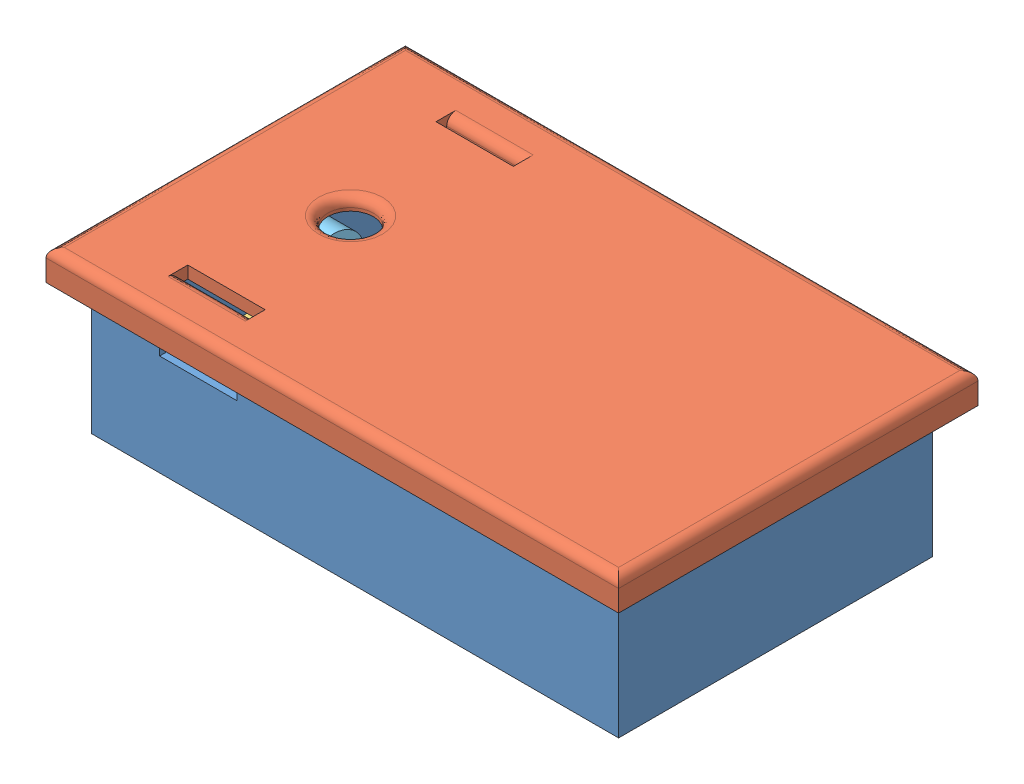
SolidWorks assembly QuadAssembly, configuration Default. Lengths in mm.
Overall size (190.29 53 118).
5 component instances, 5 part files, 12 mates.
Components (placement in the parent):
- ElectronicsHousing_QuadV2-1: ElectronicsHousing_QuadV2 [Default] at (-86.5 4 0) size (173 49 103)
- TopCover_QuadV1-1: TopCover_QuadV1 [Default] at (-86.5 49 0) x (0 0 -1) z (1 0 0) size (118 10 188)
- MockQuadPCB-1: MockQuadPCB [Default] at (-123.75 14 0) x (0 0 1) z (-1 0 0) size (89 2 84)
- 12vBatteryPack-1: 12vBatteryPack [Default] at (-38.25 4 -12.5) size (59 33.5 63.5)
- OnOffSwitch-1: OnOffSwitch [Default] at (-145 35 0) x (0 -1 0) z (-1 0 0) size (25.4 25.4 37.79)
Mates (geometry in assembly coordinates):
- Coincident2: coincident anti-aligned: plane of ElectronicsHousing_QuadV2-1 through (-86.5 0 0) normal (0 -1 0); plane of assembly through (0 0 0) normal (0 1 0)
- Coincident3: coincident aligned: plane of ElectronicsHousing_QuadV2-1 through (0 49 -51.5) normal (1 0 0); plane of assembly through (0 0 0) normal (1 0 0)
- Coincident4: coincident aligned: plane of ElectronicsHousing_QuadV2-1 through (-86.5 4 0) normal (0 0 1); plane of assembly through (0 0 0) normal (0 0 1)
- ProfileCenter1: profile center anti-aligned: plane of TopCover_QuadV1-1 through (-86.5 49 0) normal (0 -1 0); plane of ElectronicsHousing_QuadV2-1 through (-86.5 49 0) normal (0 1 0)
- Coincident6: coincident anti-aligned: plane of ElectronicsHousing_QuadV2-1 through (-86.25 14 -38) normal (0 1 0); plane of MockQuadPCB-1 through (-123.75 14 0) normal (0 -1 0)
- Width3: width anti-aligned: plane of ElectronicsHousing_QuadV2-1 through (-78.5 36 -47.5) normal (-1 0 0); plane of ElectronicsHousing_QuadV2-1 through (-169 49 0) normal (1 0 0); plane of MockQuadPCB-1 through (-81.75 16 44.5) normal (1 0 0); plane of MockQuadPCB-1 through (-165.75 16 44.5) normal (-1 0 0)
- Width4: width anti-aligned: plane of ElectronicsHousing_QuadV2-1 through (-86.5 49 47.5) normal (0 0 -1); plane of ElectronicsHousing_QuadV2-1 through (-86.5 49 -47.5) normal (0 0 1); plane of MockQuadPCB-1 through (-81.75 16 44.5) normal (0 0 1); plane of MockQuadPCB-1 through (-81.75 16 -44.5) normal (0 0 -1)
- Width5: width anti-aligned: plane of ElectronicsHousing_QuadV2-1 through (-4 49 0) normal (-1 0 0); plane of ElectronicsHousing_QuadV2-1 through (-72.5 36 -47.5) normal (1 0 0); plane of 12vBatteryPack-1 through (-8.75 37.5 -44.25) normal (1 0 0); plane of 12vBatteryPack-1 through (-67.75 37.5 -44.25) normal (-1 0 0)
- Coincident8: coincident anti-aligned: plane of ElectronicsHousing_QuadV2-1 through (-86.5 4 0) normal (0 1 0); plane of 12vBatteryPack-1 through (-38.25 4 -12.5) normal (0 -1 0)
- Width7: width anti-aligned: plane of ElectronicsHousing_QuadV2-1 through (-32.5988 29 22.5) normal (0 0 -1); plane of ElectronicsHousing_QuadV2-1 through (-86.5 49 -47.5) normal (0 0 1); plane of 12vBatteryPack-1 through (-8.75 37.5 19.25) normal (0 0 1); plane of 12vBatteryPack-1 through (-8.75 37.5 -44.25) normal (0 0 -1)
- Parallel2: parallel anti-aligned: plane of TopCover_QuadV1-1 through (-86.5 43 0) normal (0 -1 0); plane of OnOffSwitch-1 through (-180.8553 40.715 0.9775) normal (0 1 0)
- Coincident9: coincident aligned: circle of ElectronicsHousing_QuadV2-1; circle of OnOffSwitch-1
